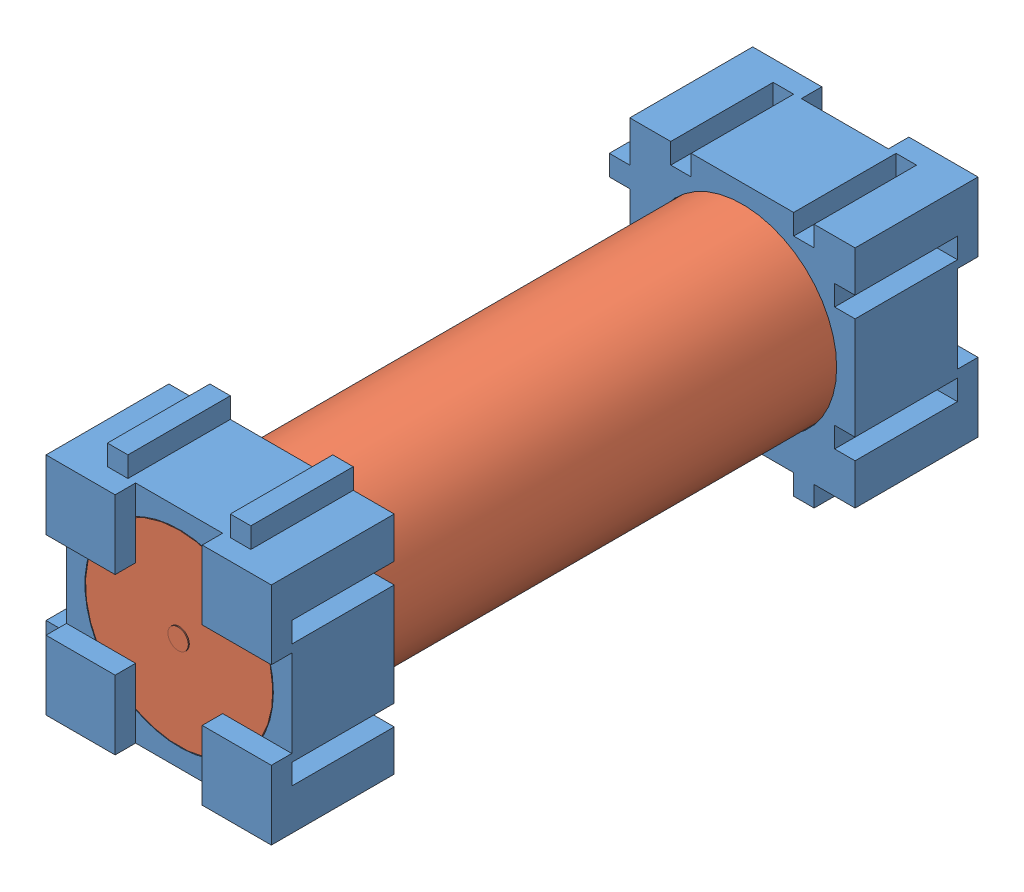
SolidWorks assembly BatteryWithCap, configuration Default. Lengths in mm.
Overall size (24 26 69).
3 component instances, 2 part files, 5 mates.
Components (placement in the parent):
- EndCap-1: EndCap [Default] at (-3.9524 14.5628 21.4054) size (24 24 12)
- HB2-1: HB2 [Default] at (-2.3515 12.807 21.4054) x (1 0 0) z (0 1 0) size (18.3 65.2 18.3)
- EndCap-2: EndCap [Default] at (-3.9524 11.0511 86.4054) x (1 0 0) z (0 0 -1) size (24 24 12)
Mates (geometry in assembly coordinates):
- Concentric1: concentric anti-aligned: circle of EndCap-1; circle of HB2-1
- Coincident1: coincident anti-aligned: plane of EndCap-1 through (-3.9524 14.5628 21.4054) normal (0 0 1); plane of HB2-1 through (-2.3515 12.807 21.4054) normal (0 0 -1)
- Concentric2: concentric aligned: circle of HB2-1; circle of EndCap-2
- Coincident2: coincident anti-aligned: plane of HB2-1 through (-2.3515 12.807 86.4054) normal (0 0 1); plane of EndCap-2 through (-3.9524 11.0511 86.4054) normal (0 0 -1)
- Parallel1: parallel anti-aligned: line of EndCap-1 through (2.6485 23.807 31.4054) axis (-1 0 0); line of EndCap-2 through (-7.3515 23.807 76.4054) axis (1 0 0)
